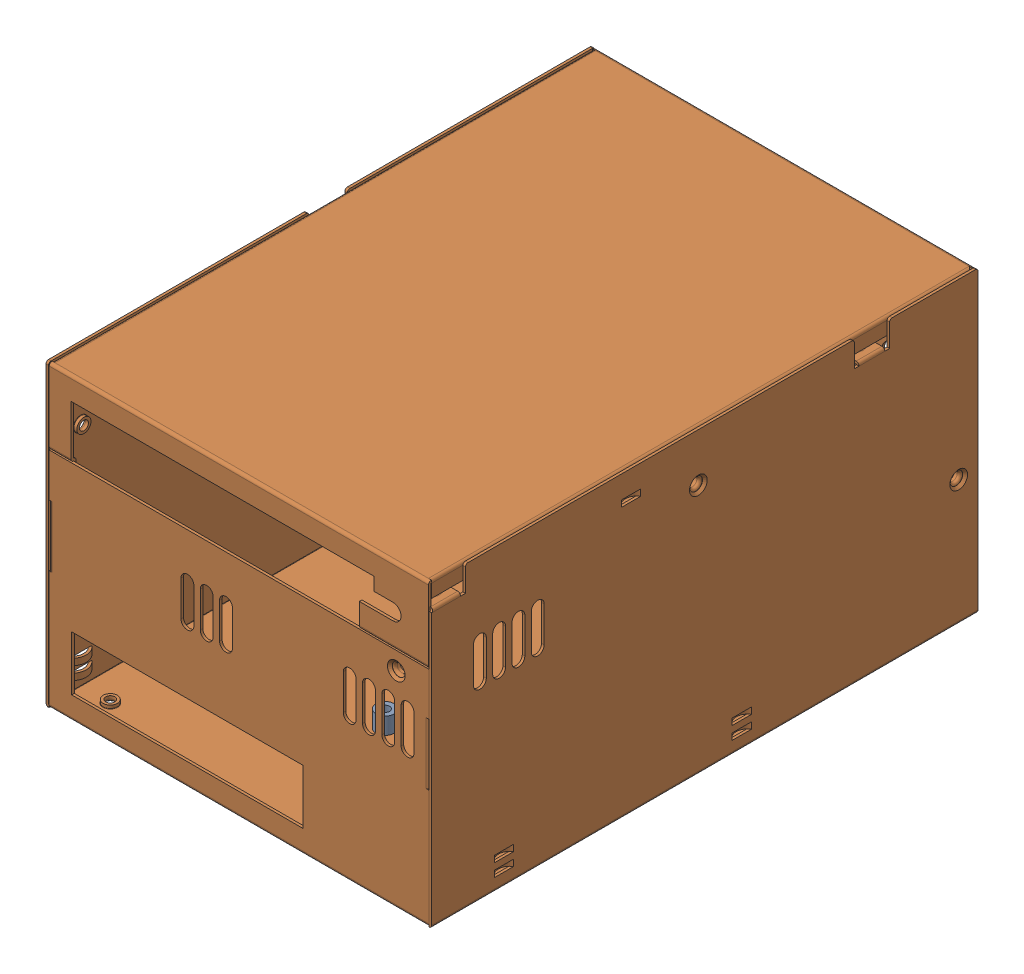
SolidWorks assembly CASE-D_ASM_2.ASM, configuration Default. Lengths in mm.
Overall size (120 93 170).
2 component instances, 2 part files, 0 mates.
Components (placement in the parent):
- CUBONE_2.PRT-1: CUBONE_2.PRT [Default] at (59.5 0.5 -46) x (-1 0 0) z (0 0 1) size (7.5 6 6.5)
- PSPA-10000-CASE-D_29.PRT-1: PSPA-10000-CASE-D_29.PRT [Default] at origin size (120 93 170)
